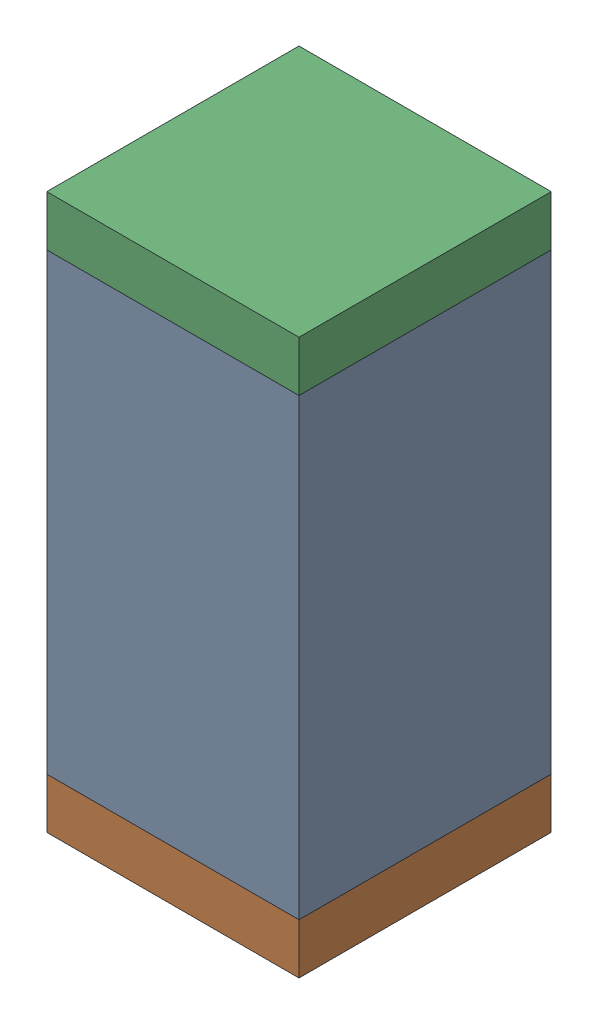
SolidWorks assembly C50, configuration Default. Lengths in mm.
Overall size (0.5 1.1 0.5).
6 component instances, 2 part files, 0 mates.
Components (placement in the parent):
- 791586336-1: 791586336 [Default] at (121.4 43.65 0) size (0.5 0.9 0.5)
  - Extruded_8-1: Extruded_8 [Default] at origin size (0.5 0.9 0.5)
- 810157360-1: 810157360 [Default] at (121.4 43.15 0) size (0.5 0.1 0.5)
  - Extruded_9-1: Extruded_9 [Default] at origin size (0.5 0.1 0.5)
- 810157360-2: 810157360 [Default] at (121.4 44.15 0) size (0.5 0.1 0.5)
  - Extruded_9-1: Extruded_9 [Default] at origin size (0.5 0.1 0.5)
